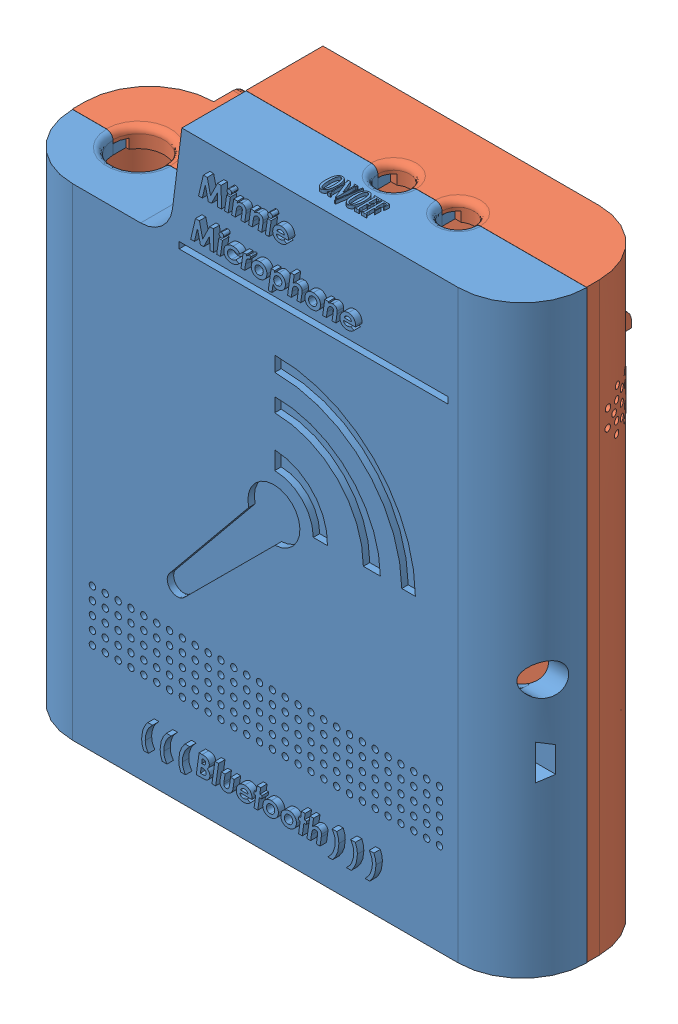
SolidWorks assembly Assem1, configuration Default. Lengths in mm.
Overall size (80.05 91.5 28.51).
6 component instances, 5 part files, 8 mates.
Components (placement in the parent):
- Top-1: Top [Default] at (39.3638 0.2274 76.2274) size (80 91.5 13)
- Bottom_clip-1: Bottom_clip [Default] at (39.3164 0.2484 54.2274) x (-1 0 0) z (0 0 -1) size (80 91 17.51)
- negative-1: negative [Default] at (9.2088 0.2484 64.2119) x (-1 0 0) z (0 0 -1) size (7 1 6)
- positive-1: positive [Default] at (9.3164 55.2484 62.4774) x (1 0 0) z (0 0 -1) size (14 3.42 8.45)
- caps-3: caps [Default] at (65.3164 5.2484 54.2585) x (1 0 0) z (0 -1 0) size (8 6 8)
- caps-4: caps [Default] at (15.3164 63.2484 54.1506) x (1 0 0) z (0 -1 0) size (8 6 8)
Mates (geometry in assembly coordinates):
- Coincident4: coincident anti-aligned: plane of Bottom_clip-1 through (69.3164 0.2484 64.2274) normal (0 1 0); plane of negative-1 through (9.2088 0.2484 64.2119) normal (0 -1 0)
- Lock1: lock: unknown of Bottom_clip-1; unknown of negative-1
- Coincident6: coincident anti-aligned: plane of Bottom_clip-1 through (69.3164 85.2484 57.2274) normal (0 0 1); plane of positive-1 through (2.3164 55.0484 57.2274) normal (0 0 -1)
- Coincident7: coincident anti-aligned: plane of Bottom_clip-1 through (2.3164 0.2484 54.2274) normal (1 0 0); plane of positive-1 through (2.3164 55.0484 64.2274) normal (-1 0 0)
- Coincident8: coincident anti-aligned: plane of Bottom_clip-1 through (2.3164 55.4484 64.2274) normal (0 -1 0); plane of positive-1 through (9.3164 55.4484 62.4774) normal (0 1 0)
- Concentric1: concentric anti-aligned: circle of Bottom_clip-1; circle of caps-4
- Concentric2: concentric anti-aligned: circle of Bottom_clip-1; circle of caps-3
- Coincident11: coincident anti-aligned: plane of Top-1 through (-0.6362 85.2274 66.2274) normal (0 0 -1); plane of Bottom_clip-1 through (39.3164 0.2484 66.2274) normal (0 0 1)
